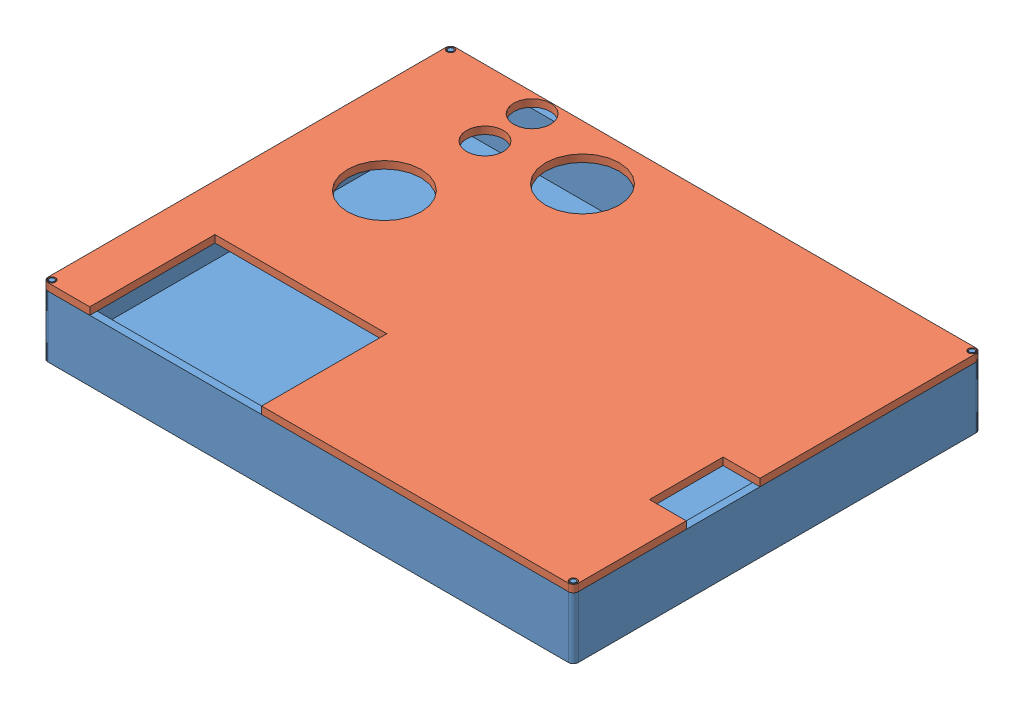
SolidWorks assembly Assemblage1, configuration Défaut. Lengths in mm.
Overall size (216 28 166).
2 component instances, 2 part files, 3 mates.
Components (placement in the parent):
- base-1: base [Défaut] at (-63.4299 -16.4355 216) size (216 28 166)
- couvercle-1: couvercle [Défaut] at (-34.8097 8.5645 319.7812) x (0 0 1) z (0 1 0) size (166 216 3)
Mates (geometry in assembly coordinates):
- Coïncidente2: coincident: plane of base-1 through (-63.4299 8.5645 216) normal (0 1 0); plane of couvercle-1 through (-34.8165 8.5645 319.7846) normal (0 -1 0)
- Coaxiale1: concentric: cylinder of base-1 through (-118.5988 11.5645 155.3118) axis (0 -1 0) radius 1; cylinder of couvercle-1 through (-118.5988 8.5645 155.3118) axis (0 1 0) radius 1.5
- Coaxiale2: concentric anti-aligned: cylinder of base-1 through (93.8012 11.5645 317.7118) axis (0 -1 0) radius 1; cylinder of couvercle-1 through (93.8012 8.5645 317.7118) axis (0 1 0) radius 1.5
